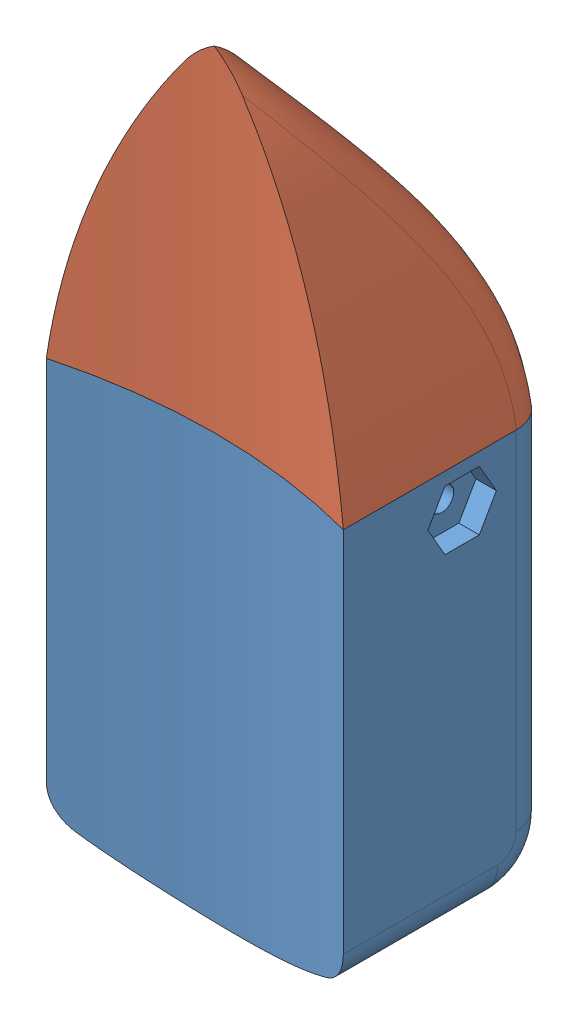
SolidWorks assembly Assem1, configuration Default. Lengths in mm.
Overall size (46.72 106.58 33.7).
2 component instances, 2 part files, 3 mates.
Components (placement in the parent):
- shellframe-1: shellframe [Default] at (-75.8277 -14.0316 24.3048) size (40.64 60.77 33.27)
- topcone-1: topcone [Default] at (-75.8277 39.3084 25.3208) x (-1 0 0) z (0 0 1) size (46.72 61.05 33.7)
Mates (geometry in assembly coordinates):
- Coincident1: coincident: plane of shellframe-1 through (-96.1477 39.3084 49.7048) normal (0 1 0); plane of topcone-1 through (-76.1515 39.3084 24.9039) normal (0 -1 0)
- Concentric1: concentric: cylinder of shellframe-1 through (-75.8277 80.1404 129.2068) axis (0 -1 0) radius 78.232; cylinder of topcone-1 through (-75.8277 90.1084 129.2068) axis (0 -1 0) radius 78.232
- Coincident3: coincident: line of shellframe-1 through (-96.1477 39.3084 53.6598) axis (0 0 -1); line of topcone-1 through (-96.1477 39.3084 53.6598) axis (0 0 -1)
